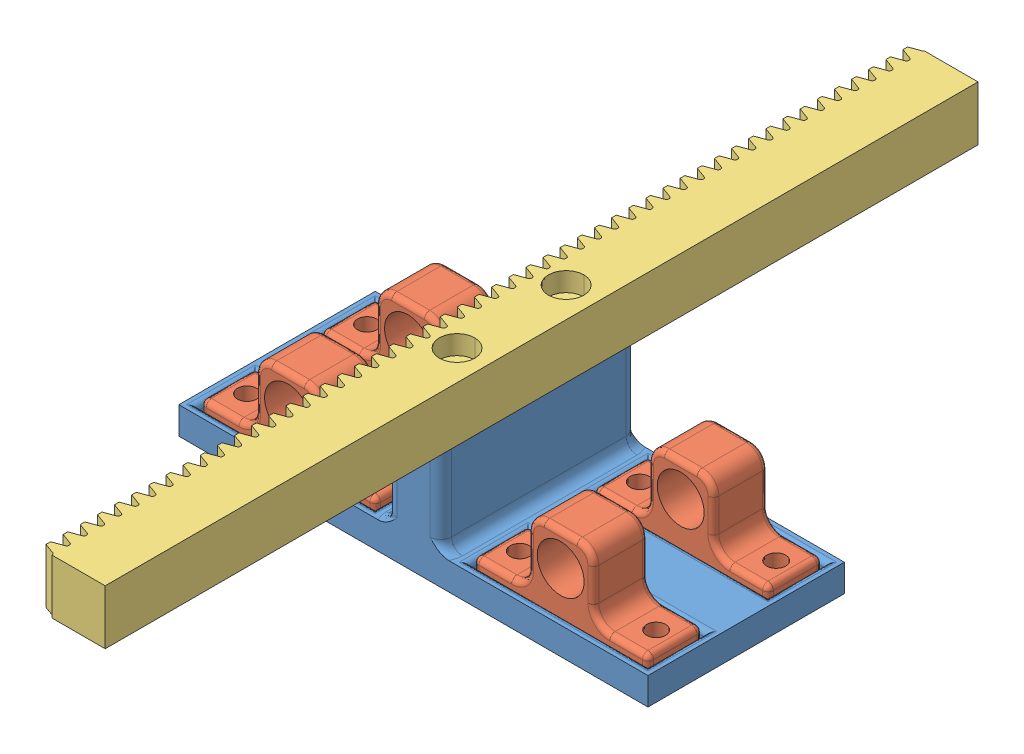
SolidWorks assembly Assem1, configuration ﾃﾞﾌｫﾙﾄ. Lengths in mm.
Overall size (86 31.5 160).
6 component instances, 3 part files, 15 mates.
Components (placement in the parent):
- stage_y-1: stage_y [ﾃﾞﾌｫﾙﾄ] at (-18.9947 2.4951 86) size (86 21.5 36)
- bush_8-2: bush_8 [ﾃﾞﾌｫﾙﾄ] at (-44.9947 15.4951 80) x (1 0 0) z (0 0 -1) size (32 15 10)
- bush_8-3: bush_8 [ﾃﾞﾌｫﾙﾄ] at (-44.9947 15.4951 102) x (1 0 0) z (0 0 -1) size (32 15 10)
- bush_8-4: bush_8 [ﾃﾞﾌｫﾙﾄ] at (5.0053 15.4951 80) x (1 0 0) z (0 0 -1) size (32 15 10)
- bush_8-5: bush_8 [ﾃﾞﾌｫﾙﾄ] at (5.0053 15.4951 102) x (1 0 0) z (0 0 -1) size (32 15 10)
- RGEABL1_0Z_160_A70_B20-1: RGEABL1_0Z_160_A70_B20 [Default] at (-13.4947 23.9951 166) x (0 0 -1) z (0 1 0) size (160 12 10)
Mates (geometry in assembly coordinates):
- 一致1: coincident anti-aligned: plane of stage_y-1 through (-18.9947 5.4951 86) normal (0 1 0); plane of bush_8-3 through (-44.9947 5.4951 92) normal (0 -1 0)
- 同心円1: concentric aligned: cylinder of stage_y-1 through (-56.4947 2.4951 97) axis (0 1 0) radius 1.75; cylinder of bush_8-3 through (-56.4947 5.4951 97) axis (0 1 0) radius 1.75
- 同心円2: concentric aligned: cylinder of stage_y-1 through (-31.4947 2.4951 97) axis (0 1 0) radius 1.75; cylinder of bush_8-3 through (-31.4947 5.4951 97) axis (0 1 0) radius 1.75
- 同心円3: concentric aligned: cylinder of stage_y-1 through (-6.4947 2.4951 97) axis (0 1 0) radius 1.75; cylinder of bush_8-5 through (-6.4947 5.4951 97) axis (0 1 0) radius 1.75
- 同心円4: concentric aligned: cylinder of stage_y-1 through (18.5053 2.4951 97) axis (0 1 0) radius 1.75; cylinder of bush_8-5 through (18.5053 5.4951 97) axis (0 1 0) radius 1.75
- 一致3: coincident anti-aligned: plane of stage_y-1 through (-18.9947 5.4951 86) normal (0 1 0); plane of bush_8-5 through (5.0053 5.4951 92) normal (0 -1 0)
- 同心円5: concentric aligned: cylinder of stage_y-1 through (18.5053 2.4951 75) axis (0 1 0) radius 1.75; cylinder of bush_8-4 through (18.5053 5.4951 75) axis (0 1 0) radius 1.75
- 同心円6: concentric aligned: cylinder of stage_y-1 through (-6.4947 2.4951 75) axis (0 1 0) radius 1.75; cylinder of bush_8-4 through (-6.4947 5.4951 75) axis (0 1 0) radius 1.75
- 一致4: coincident anti-aligned: plane of stage_y-1 through (-18.9947 5.4951 86) normal (0 1 0); plane of bush_8-4 through (5.0053 5.4951 70) normal (0 -1 0)
- 同心円7: concentric aligned: cylinder of stage_y-1 through (-31.4947 2.4951 75) axis (0 1 0) radius 1.75; cylinder of bush_8-2 through (-31.4947 5.4951 75) axis (0 1 0) radius 1.75
- 同心円8: concentric aligned: cylinder of stage_y-1 through (-56.4947 2.4951 75) axis (0 1 0) radius 1.75; cylinder of bush_8-2 through (-56.4947 5.4951 75) axis (0 1 0) radius 1.75
- 一致5: coincident anti-aligned: plane of stage_y-1 through (-18.9947 5.4951 86) normal (0 1 0); plane of bush_8-2 through (-44.9947 5.4951 70) normal (0 -1 0)
- 同心円9: concentric aligned: cylinder of stage_y-1 through (-18.9947 2.4951 76) axis (0 1 0) radius 1.75; cylinder of RGEABL1_0Z_160_A70_B20-1 through (-18.9947 23.9951 76) axis (0 1 0) radius 1.75
- 同心円10: concentric aligned: cylinder of stage_y-1 through (-18.9947 2.4951 96) axis (0 1 0) radius 1.75; cylinder of RGEABL1_0Z_160_A70_B20-1 through (-18.9947 23.9951 96) axis (0 1 0) radius 1.75
- 一致6: coincident anti-aligned: plane of stage_y-1 through (-18.9947 23.9951 86) normal (0 1 0); plane of RGEABL1_0Z_160_A70_B20-1 through (-13.4947 23.9951 166) normal (0 -1 0)
